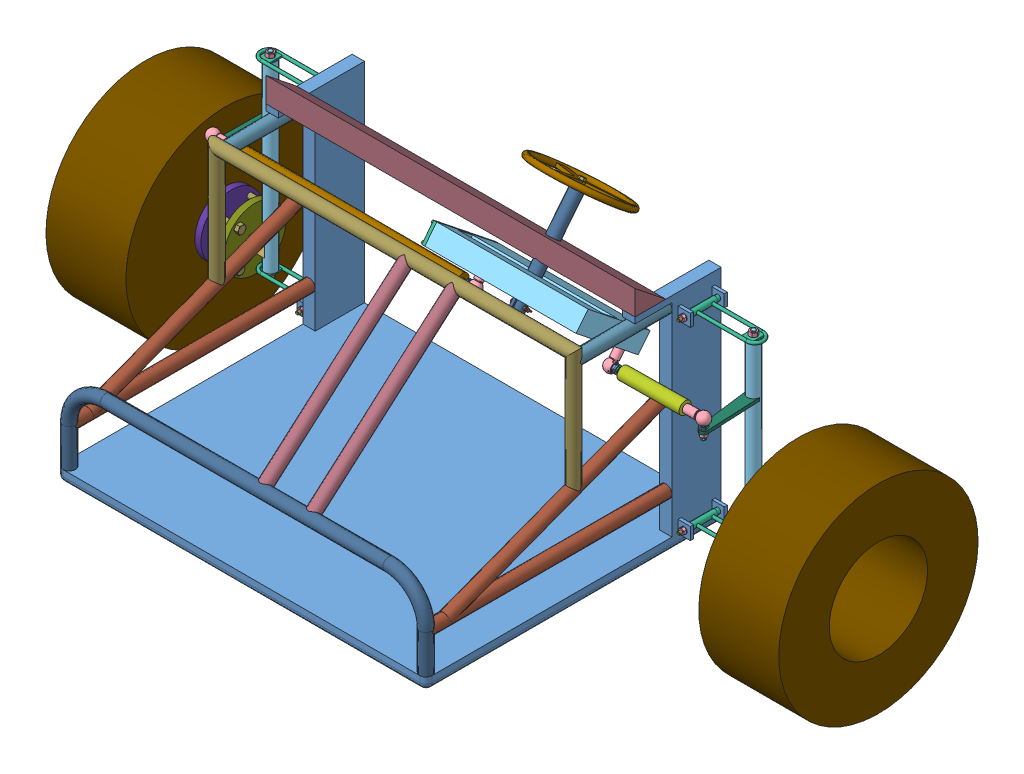
SolidWorks assembly FCA1, configuration Default. Lengths in mm.
Overall size (1513.16 852.83 849.49).
103 component instances, 32 part files, 159 mates.
Components (placement in the parent):
- FCP1-1: FCP1 [Default] at origin size (812.8 457.2 609.6)
- STA1-2: STA1 [Default] at (558.8 334.6162 -409.4012) x (-0.999987 0.003219 0.004024) z (0 0.780869 -0.624695) size (320.68 259.28 240.21)
  - STP10-3: STP10 [Default] at origin size (304.8 155.79 25.4)
    - spur gear_ai-4: spur gear_ai [Inch - Spur gear 6DP 25T 20PA 1FW ---S25N3.0H2.0L1.0S1] x (0 0 1) z (-0.989908 0.141715 0) size (25.4 113.98 114.2)
    - rack spur rectangular_ai-2: rack spur rectangular_ai [Inch - Rack-spur - rectangular 6DP 20PA 1FW 1.5PH 12L---SAll] at (-154.037 -91.44 25.4) size (304.8 42.33 25.4)
  - STP01-11: STP01 [Default] at (138.063 -75.0375 -39.3517) x (0 1 0) z (0 0 -1) size (23.88 20.07 47.75)
  - STP03-3: STP03 [Default] at (150.763 -97.79 31.75) x (0 0 -1) z (1 0 0) size (39.69 165.1 311.15)
  - STP04-3: STP04 [Default] at (150.763 -97.79 -7.9375) x (0 0 1) z (-1 0 0) size (39.69 165.1 6.59)
  - socket head cap screw_ai-1: socket head cap screw_ai [HX-SHCS 0.125-40x0.5x0.5-N] at (160.288 64.135 28.575) x (-1 0 0) z (0 0.866025 0.5) size (15.88 5.21 5.21)
  - socket head cap screw_ai-2: socket head cap screw_ai [HX-SHCS 0.125-40x0.5x0.5-N] at (160.288 64.135 -4.7625) x (-1 0 0) z (0 0.866025 0.5) size (15.88 5.21 5.21)
  - socket head cap screw_ai-4: socket head cap screw_ai [HX-SHCS 0.125-40x0.5x0.5-N] at (160.288 -94.615 28.575) x (-1 0 0) z (0 0.866025 0.5) size (15.88 5.21 5.21)
  - socket head cap screw_ai-7: socket head cap screw_ai [HX-SHCS 0.125-40x0.5x0.5-N] at (160.288 -94.615 -4.7625) x (-1 0 0) z (0 0.866025 0.5) size (15.88 5.21 5.21)
  - STP01-10: STP01 [Default] at (-141.337 -75.0375 -39.3517) x (0 -1 0) z (0 0 -1) size (23.88 20.07 47.75)
  - STP05-2: STP05 [Default] at (-154.037 -58.6317 0) x (1 0 0) z (0 0 -1) size (304.8 32.77 26.99)
  - STP06-1: STP06 [Default] at (-0.0036 -0.0251 180.975) x (0.5 -0.866025 0) z (0 0 1) size (189.81 189.81 12.01)
  - STP07-1: STP07 [Default] at (-0.0036 -0.0251 -33.528) x (-0.141715 -0.989908 0) z (0 0 1) size (28 24.77 211.33)
  - FWP4-1: FWP4 [Default] at (-20.7057 3.2593 -20.828) x (0 0 1) z (0.989908 -0.141715 0) size (12.7 12.7 39.95)
  - hex bolt_ai-1: hex bolt_ai [HBOLT 0.2500-20x0.75x0.75-N] at (-0.0036 -0.0251 188.9252) x (0 0 -1) z (0.5 0.866025 0) size (23.83 12.85 11.13)
- STP08-1: STP08 [Default] at (469.9 381 -431.8) x (0 0 -1) z (1 0 0) size (63.5 50.8 762)
- STP02-1: STP02 [Default] at (889.5958 256.5577 -445.8437) x (-0.961205 0 0.275836) z (0 1 0) size (16.51 16.51 46.05)
- SP3-1: SP3 [Default] at (889.5958 238.8316 -445.8437) x (-0.086724 0 -0.996232) z (0 -1 0) size (120.39 25.32 6.35)
- FWA1-1: FWA1 [Default] at (1025.989 75.5387 -589.4868) x (0 -0.682582 -0.730809) z (-1 0 0) size (411.48 411.48 257.81)
  - FWP5-2: FWP5 [Default] at (27.9791 75.0582 101.7677) size (127 127 48.26)
  - FWP1-1: FWP1 [Default] at (27.9791 75.0582 53.5077) size (127 127 48.26)
  - EB2-1: EB2 [Default] at (27.9791 75.0582 50.3327) x (-1 0 0) z (0 0 1) size (411.48 411.48 165.1)
  - internal tooth-lock washers_ai-1: internal tooth-lock washers_ai [Internal Tooth LW Type A-0.375] at (78.7791 75.0582 49.3167) x (0.992449 -0.122662 0) z (-0.122662 -0.992449 0) size (17.58 1.02 17.58)
  - internal tooth-lock washers_ai-2: internal tooth-lock washers_ai [Internal Tooth LW Type A-0.375] at (-22.8209 75.0582 49.3167) x (0.730809 -0.682582 0) z (-0.682582 -0.730809 0) size (17.58 1.02 17.58)
  - FWP2-2: FWP2 [Default] at (27.9791 75.0582 114.4677) x (-0.730809 0.682582 0) z (0 0 -1) size (9.53 9.53 14.29)
  - FWP3-2: FWP3 [Default] at (19.3103 65.7769 130.3427) x (0 0 1) z (-0.730809 0.682582 0) size (31.75 25.4 25.4)
  - FWP4-1: FWP4 [Default] at (13.8923 59.9761 123.9927) x (-0.730809 0.682582 0) z (0.682582 0.730809 0) size (12.7 12.7 39.95)
  - hex nut_ai-5: hex nut_ai [HNUT 0.4375-20-D-N] at (78.7791 75.0582 49.3167) x (0.291608 -0.956538 0) z (0 0 1) size (17.48 20.18 9.78)
  - internal tooth-lock washers_ai-5: internal tooth-lock washers_ai [Internal Tooth LW Type A-0.375] at (27.9791 24.2582 49.3167) x (-0.875007 -0.484111 0) z (-0.484111 0.875007 0) size (17.58 1.02 17.58)
  - internal tooth-lock washers_ai-6: internal tooth-lock washers_ai [Internal Tooth LW Type A-0.375] at (27.9791 125.8582 49.3167) x (0.730809 -0.682582 0) z (-0.682582 -0.730809 0) size (17.58 1.02 17.58)
  - hex nut_ai-7: hex nut_ai [HNUT 0.4375-20-D-N] at (-22.8209 75.0582 49.3167) x (0.291608 -0.956538 0) z (0 0 1) size (17.48 20.18 9.78)
  - hex nut_ai-8: hex nut_ai [HNUT 0.4375-20-D-N] at (27.9791 24.2582 39.5377) x (-0.97419 0.225729 0) z (0 0 -1) size (17.48 20.18 9.78)
  - hex nut_ai-9: hex nut_ai [HNUT 0.4375-20-D-N] at (27.9791 125.8582 49.3167) x (-0.97419 0.225729 0) z (0 0 1) size (17.48 20.18 9.78)
  - hex bolt_ai-1: hex bolt_ai [HBOLT 0.4375-20x3x1.125-N] at (78.7791 75.0582 122.4941) x (0 0 -1) z (-0.291608 0.956538 0) size (84.23 18.33 15.88)
  - hex bolt_ai-2: hex bolt_ai [HBOLT 0.4375-20x3x1.125-N] at (27.9791 125.8582 122.4941) x (0 0 -1) z (0.682582 0.730809 0) size (84.23 18.33 15.88)
  - hex bolt_ai-3: hex bolt_ai [HBOLT 0.4375-20x3x1.125-N] at (-22.8209 75.0582 122.4941) x (0 0 -1) z (0.97419 -0.225729 0) size (84.23 18.33 15.88)
  - hex bolt_ai-6: hex bolt_ai [HBOLT 0.4375-20x3x1.125-N] at (27.9791 24.2582 122.4941) x (0 0 -1) z (0.97419 -0.225729 0) size (84.23 18.33 15.88)
- SA1-3: SA1 [Default] at (902.3249 84.601 -573.897) x (-0.581832 0 -0.813309) z (0 1 0) size (129.23 145.39 403.48)
  - SS1-1: SS1 [Default] at (0.7633 27.1847 256.5845) x (1 0 0) z (0 0 1) size (25.4 25.4 403.48)
  - SP2-2: SP2 [Default] at (87.3872 94.4048 258.172) x (0.581832 0.813309 0) z (-0.813309 0.581832 0) size (133.34 12.7 63.5)
  - SP2-3: SP2 [Default] at (87.3872 94.4048 -122.701) x (0.581832 0.813309 0) z (-0.813309 0.581832 0) size (133.34 12.7 63.5)
  - hex nut_ai-3: hex nut_ai [HNUT 0.3750-24-D-N] at (0.7633 27.1846 -132.8483) x (0.910536 0.41343 0) z (0 0 -1) size (14.27 16.48 8.56)
  - hex nut_ai-4: hex nut_ai [HNUT 0.3750-24-D-N] at (0.7633 27.1847 268.3193) x (0.910536 0.41343 0) z (0 0 1) size (14.27 16.48 8.56)
- STP09-1: STP09 [Default] at (724.7148 240.1747 -456.9263) x (0.009813 0 0.999952) z (-0.999952 0 0.009813) size (25.4 25.4 152.4)
- STP02-2: STP02 [Default] at (699.7485 256.5577 -443.9807) x (-0.004906 -0.866025 -0.499976) z (-0.999952 0 0.009813) size (16.51 16.51 46.05)
- STP01-3: STP01 [Default] at (889.5958 256.5577 -445.8437) x (0.009813 0 0.999952) z (0.999952 0 -0.009813) size (23.88 20.07 47.75)
- hex bolt_ai-1: hex bolt_ai [HBOLT 0.2500-20x3.5x0.75-N] at (774.7 342.9 -601.6752) x (0 0 1) z (-1 0 0) size (93.68 12.85 11.13)
- external tooth lock washer_ai-1: external tooth lock washer_ai [ASME B18.21.1 - 0.256] at (774.7 342.9 -520.7) x (0 0 -1) z (0.999649 0.026486 0) size (0.58 12.4 12.55)
- hex nut_ai-1: hex nut_ai [HNUT 0.2500-28-D-N] at (774.7 342.9 -514.3754) x (0.5 -0.866025 0) z (0 0 1) size (11.11 12.83 5.74)
- hex bolt_ai-2: hex bolt_ai [HBOLT 0.2500-20x3.5x0.75-N] at (774.7 -38.1 -601.6752) x (0 0 1) z (-0.5 0.866025 0) size (93.68 12.85 11.13)
- external tooth lock washer_ai-2: external tooth lock washer_ai [ASME B18.21.1 - 0.256] at (774.7 -38.1 -520.7) x (0 0 -1) z (0.643979 -0.765044 0) size (0.58 12.4 12.55)
- hex nut_ai-2: hex nut_ai [HNUT 0.2500-28-D-N] at (774.7 -38.1 -514.3754) x (0.5 -0.866025 0) z (0 0 1) size (11.11 12.83 5.74)
- FWA1-2: FWA1 [Default] at (-263.989 -72.2367 -589.4868) x (0 0.682582 -0.730809) z (1 0 0) size (411.48 411.48 257.81)
  - FWP5-2: FWP5 [Default] at (27.9791 75.0582 101.7677) size (127 127 48.26)
  - FWP1-1: FWP1 [Default] at (27.9791 75.0582 53.5077) size (127 127 48.26)
  - EB2-1: EB2 [Default] at (27.9791 75.0582 50.3327) x (-1 0 0) z (0 0 1) size (411.48 411.48 165.1)
  - internal tooth-lock washers_ai-1: internal tooth-lock washers_ai [Internal Tooth LW Type A-0.375] at (78.7791 75.0582 49.3167) x (0.992449 -0.122662 0) z (-0.122662 -0.992449 0) size (17.58 1.02 17.58)
  - internal tooth-lock washers_ai-2: internal tooth-lock washers_ai [Internal Tooth LW Type A-0.375] at (-22.8209 75.0582 49.3167) x (0.730809 -0.682582 0) z (-0.682582 -0.730809 0) size (17.58 1.02 17.58)
  - FWP2-2: FWP2 [Default] at (27.9791 75.0582 114.4677) x (-0.730809 0.682582 0) z (0 0 -1) size (9.53 9.53 14.29)
  - FWP3-2: FWP3 [Default] at (19.3103 65.7769 130.3427) x (0 0 1) z (-0.730809 0.682582 0) size (31.75 25.4 25.4)
  - FWP4-1: FWP4 [Default] at (13.8923 59.9761 123.9927) x (-0.730809 0.682582 0) z (0.682582 0.730809 0) size (12.7 12.7 39.95)
  - hex nut_ai-5: hex nut_ai [HNUT 0.4375-20-D-N] at (78.7791 75.0582 49.3167) x (0.291608 -0.956538 0) z (0 0 1) size (17.48 20.18 9.78)
  - internal tooth-lock washers_ai-5: internal tooth-lock washers_ai [Internal Tooth LW Type A-0.375] at (27.9791 24.2582 49.3167) x (-0.875007 -0.484111 0) z (-0.484111 0.875007 0) size (17.58 1.02 17.58)
  - internal tooth-lock washers_ai-6: internal tooth-lock washers_ai [Internal Tooth LW Type A-0.375] at (27.9791 125.8582 49.3167) x (0.730809 -0.682582 0) z (-0.682582 -0.730809 0) size (17.58 1.02 17.58)
  - hex nut_ai-7: hex nut_ai [HNUT 0.4375-20-D-N] at (-22.8209 75.0582 49.3167) x (0.291608 -0.956538 0) z (0 0 1) size (17.48 20.18 9.78)
  - hex nut_ai-8: hex nut_ai [HNUT 0.4375-20-D-N] at (27.9791 24.2582 39.5377) x (-0.97419 0.225729 0) z (0 0 -1) size (17.48 20.18 9.78)
  - hex nut_ai-9: hex nut_ai [HNUT 0.4375-20-D-N] at (27.9791 125.8582 49.3167) x (-0.97419 0.225729 0) z (0 0 1) size (17.48 20.18 9.78)
  - hex bolt_ai-1: hex bolt_ai [HBOLT 0.4375-20x3x1.125-N] at (78.7791 75.0582 122.4941) x (0 0 -1) z (-0.291608 0.956538 0) size (84.23 18.33 15.88)
  - hex bolt_ai-2: hex bolt_ai [HBOLT 0.4375-20x3x1.125-N] at (27.9791 125.8582 122.4941) x (0 0 -1) z (0.682582 0.730809 0) size (84.23 18.33 15.88)
  - hex bolt_ai-3: hex bolt_ai [HBOLT 0.4375-20x3x1.125-N] at (-22.8209 75.0582 122.4941) x (0 0 -1) z (0.97419 -0.225729 0) size (84.23 18.33 15.88)
  - hex bolt_ai-6: hex bolt_ai [HBOLT 0.4375-20x3x1.125-N] at (27.9791 24.2582 122.4941) x (0 0 -1) z (0.97419 -0.225729 0) size (84.23 18.33 15.88)
- SA1-4: SA1 [Default] at (-140.3249 220.199 -573.897) x (0.581832 0 -0.813309) z (0 -1 0) size (129.23 145.39 403.48)
  - SS1-1: SS1 [Default] at (0.7633 27.1847 256.5845) x (1 0 0) z (0 0 1) size (25.4 25.4 403.48)
  - SP2-2: SP2 [Default] at (87.3872 94.4048 258.172) x (0.581832 0.813309 0) z (-0.813309 0.581832 0) size (133.34 12.7 63.5)
  - SP2-3: SP2 [Default] at (87.3872 94.4048 -122.701) x (0.581832 0.813309 0) z (-0.813309 0.581832 0) size (133.34 12.7 63.5)
  - hex nut_ai-3: hex nut_ai [HNUT 0.3750-24-D-N] at (0.7633 27.1846 -132.8483) x (0.910536 0.41343 0) z (0 0 -1) size (14.27 16.48 8.56)
  - hex nut_ai-4: hex nut_ai [HNUT 0.3750-24-D-N] at (0.7633 27.1847 268.3193) x (0.910536 0.41343 0) z (0 0 1) size (14.27 16.48 8.56)
- hex bolt_ai-4: hex bolt_ai [HBOLT 0.2500-20x3.5x0.75-N] at (-12.7 342.9 -601.6752) x (0 0 1) z (-1 0 0) size (93.68 12.85 11.13)
- external tooth lock washer_ai-9: external tooth lock washer_ai [ASME B18.21.1 - 0.256] at (-12.7 342.9 -520.7) x (0 0 -1) z (0.602564 -0.798071 0) size (0.58 12.4 12.55)
- hex nut_ai-3: hex nut_ai [HNUT 0.2500-28-D-N] at (-12.7 342.9 -514.3754) size (11.11 12.83 5.74)
- SP3-2: SP3 [Default] at (-123.1466 232.2195 -445.5445) x (0.047449 0 -0.998874) z (0 1 0) size (120.39 25.32 6.35)
- hex nut_ai-4: hex nut_ai [HNUT 0.3125-24-D-N] at (889.5958 225.5474 -445.8437) x (0.986789 0 0.162012) z (0 -1 0) size (12.7 14.66 6.93)
- STP010-1: STP010 [Default] at (395.2241 278.1416 -442.6472) x (-0.002815 -0.625306 0.780375) z (0.999986 0.00167 0.004946) size (25.4 25.4 508)
- STP02-3: STP02 [Default] at (420.3522 257.4571 -442.8565) x (0.004395 -0.780378 -0.625293) z (0.999986 0.00167 0.004946) size (16.51 16.51 46.05)
- STP02-4: STP02 [Default] at (-123.1466 256.5497 -445.5445) x (0.666341 0 0.745647) z (0 1 0) size (16.51 16.51 46.05)
- hex nut_ai-5: hex nut_ai [HNUT 0.3125-24-D-N] at (-123.1466 225.2853 -445.5445) x (-0.977382 0 -0.211483) z (0 -1 0) size (12.7 14.66 6.93)
- STP01-5: STP01 [Default] at (-123.1466 256.5497 -445.5445) x (0.005218 -0.342016 -0.93968) z (-0.999986 -0.00167 -0.004946) size (23.88 20.07 47.75)
- hex bolt_ai-5: hex bolt_ai [HBOLT 0.2500-20x3.5x0.75-N] at (-12.7 -37.973 -601.6752) x (0 0 1) z (-1 0 0) size (93.68 12.85 11.13)
- external tooth lock washer_ai-10: external tooth lock washer_ai [ASME B18.21.1 - 0.256] at (-12.7 -37.973 -520.7) x (0 0 -1) z (0.999649 -0.026486 0) size (0.58 12.4 12.55)
- hex nut_ai-6: hex nut_ai [HNUT 0.2500-28-D-N] at (-12.7 -37.973 -520.1158) x (0.5 0.866025 0) z (0 0 -1) size (11.11 12.83 5.74)
- FCP2-1: FCP2 [Default] at (12.7 -50.8 -12.7) size (762 168.4 25.4)
- FCP3-1: FCP3 [Default] at (12.7 25.4 -508) x (0.992649 -0.121026 0) z (0 0 1) size (25.4 25.4 495.3)
- FCP3-2: FCP3 [Default] at (749.3 25.4 -508) size (25.4 25.4 495.3)
- FCP3-4: FCP3 [Default] at (12.7 25.4 -50.8) x (0.846332 0.498186 0.188503) z (0 0.353892 -0.935286) size (25.4 25.4 495.3)
- FCP4-1: FCP4 [Default] at (12.7 127 -317.5) size (762 254 25.4)
- FCP3-6: FCP3 [Default] at (749.3 200.6828 -514.0473) x (1 0 0) z (0 -0.353892 0.935286) size (25.4 25.4 495.3)
- FCP5-1: FCP5 [Default] at (408.6538 104.14 -15.24) x (1 0 0) z (0 -0.658057 0.752969) size (25.4 25.4 401.32)
- FCP5-2: FCP5 [Default] at (508 104.14 -15.24) x (1 0 0) z (0 -0.658057 0.752969) size (25.4 25.4 401.32)
- FCP6-1: FCP6 [Default] at (749.3 355.6 -508) size (25.4 25.4 190.5)
- FCP6-2: FCP6 [Default] at (12.7 355.6 -508) size (25.4 25.4 190.5)
Mates (geometry in assembly coordinates):
- Coincident9: coincident: line of FCP1-1 through (0 381 -609.6) axis (0 0 1); line of STP08-1 through (0 381 -495.3) axis (0 0 1)
- Concentric33: concentric: cylinder of STP02-1 through (889.5958 218.7656 -445.8437) axis (0 1 0) radius 3.4544; circle of SP3-1
- Coincident47: coincident: plane of STP02-1 through (889.5958 238.8316 -445.8437) normal (0 -1 0); circle of SP3-1
- Concentric3939: concentric: circle of FCP1-1; circle of SA1-3/SP2-3
- Coincident5481: coincident: plane of FCP1-1 through (693.6084 0 -590.55) normal (0 0 1); circle of SA1-3/SP2-3
- Angle15: planar angle = 0 rad: plane of SA1-3/SP2-3 through (868.3413 -38.1 -545.592) normal (-1 0 0); plane of FCP1-1 through (736.6 355.6 -25.4) normal (-1 0 0)
- Lock2: lock: unknown of ?; unknown of STP08-1
- Lock3: lock: unknown of FCP1-1; unknown of STP08-1
- Concentric3947: concentric: sphere of STA1-2/STP01-10; sphere of STP02-2
- Angle17: planar angle = 3.141593 rad: plane of STP01-3 through (889.4712 248.6837 -458.5431) normal (0 -1 0); plane of FCP1-1 through (0 -76.2 765.8005) normal (0 -1 0)
- Concentric3948: concentric: sphere of STP02-1; sphere of STP01-3
- Concentric3949: concentric: cylinder of SP3-1 through (879.7713 238.8316 -558.7009) axis (0 -1 0) radius 12.7; cylinder of SA1-3/SS1-1 through (879.7713 -36.5125 -558.7009) axis (0 1 0) radius 12.7
- Concentric3950: concentric: cylinder of FWA1-1/FWP3-2 through (879.7713 -11.1125 -558.7009) axis (0 1 0) radius 12.7; cylinder of SA1-3/SS1-1 through (879.7713 -36.5125 -558.7009) axis (0 1 0) radius 12.7
- Angle18: planar angle = 0 rad: plane of FWA1-1/FWP3-2 through (895.6463 -11.1125 -571.4009) normal (0 0 -1); plane of FCP1-1 through (0 0 -609.6) normal (0 0 -1)
- Distance6: distance = 25.4 mm: plane of FWA1-1/FWP3-2 through (895.6463 -11.1125 -558.7009) normal (0 -1 0); plane of SA1-3/SP2-3 through (774.7 -36.5125 -545.592) normal (0 1 0)
- Concentric3953: concentric: circle of STP09-1; circle of STP02-2
- Coincident5483: coincident: plane of STP09-1 through (737.5389 256.5577 -444.3516) normal (-0.999952 0 0.009813); circle of STP02-2
- Concentric3955: concentric: circle of STP09-1; circle of STP01-3
- Coincident5484: coincident: circle of STP09-1; cone of STP01-3 through (876.8964 256.5577 -445.7191) axis (0.999952 0 -0.009813)
- Concentric39561: concentric: cylinder of FCP1-1 through (774.7 342.9 -520.7) axis (0 0 -1) radius 4.7625; cylinder of hex bolt_ai-1 through (774.7 342.9 -601.6752) axis (0 0 -1) radius 3.175
- Coincident54851: coincident: plane of FCP1-1 through (0 0 -596.9) normal (0 0 -1); plane of hex bolt_ai-1 through (774.7 349.3231 -596.9) normal (0 0 1)
- Concentric39571: concentric: cylinder of FCP1-1 through (774.7 342.9 -520.7) axis (0 0 -1) radius 4.7625; cylinder of external tooth lock washer_ai-1 through (774.7 342.9 -485.775) axis (0 0 1) radius 3.2512
- Coincident54861: coincident: plane of FCP1-1 through (0 0 -520.7) normal (0 0 1); plane of external tooth lock washer_ai-1 through (774.6139 346.1501 -520.7) normal (0 0 -1)
- Concentric39581: concentric: cylinder of external tooth lock washer_ai-1 through (774.7 342.9 -520.1158) axis (0 0 -1) radius 4.7625; cylinder of hex nut_ai-1 through (774.7 342.9 -539.4129) axis (0 0 1) radius 3.175
- Coincident54871: coincident: plane of external tooth lock washer_ai-1 through (774.5338 349.1716 -520.1158) normal (0 0 1); plane of hex nut_ai-1 through (780.2563 346.1079 -520.1158) normal (0 0 -1)
- Concentric39601: concentric: cylinder of FCP1-1 through (774.7 -38.1 -520.7) axis (0 0 -1) radius 4.7625; cylinder of hex bolt_ai-2 through (774.7 -38.1 -601.6752) axis (0 0 -1) radius 3.175
- Coincident54891: coincident: plane of FCP1-1 through (0 304.8 -596.9) normal (0 0 -1); plane of hex bolt_ai-2 through (780.2626 -34.8884 -596.9) normal (0 0 1)
- Concentric39611: concentric: cylinder of FCP1-1 through (774.7 -38.1 -520.7) axis (0 0 -1) radius 4.7625; cylinder of external tooth lock washer_ai-2 through (774.7 -38.1 -485.775) axis (0 0 1) radius 3.2512
- Coincident54901: coincident: plane of FCP1-1 through (0 304.8 -520.7) normal (0 0 1); plane of external tooth lock washer_ai-2 through (777.1873 -36.0063 -520.7) normal (0 0 -1)
- Concentric39621: concentric: cylinder of external tooth lock washer_ai-2 through (774.7 -38.1 -520.1158) axis (0 0 -1) radius 4.7625; cylinder of hex nut_ai-2 through (774.7 -38.1 -539.4129) axis (0 0 1) radius 3.175
- Coincident54911: coincident: plane of external tooth lock washer_ai-2 through (779.4997 -34.0598 -520.1158) normal (0 0 1); plane of hex nut_ai-2 through (780.2563 -34.8921 -520.1158) normal (0 0 -1)
- Concentric3964: concentric: circle of FCP1-1; circle of SA1-4/SP2-3
- Coincident5492: coincident: plane of FCP1-1 through (411.331 355.6 -527.05) normal (0 0 -1); circle of SA1-4/SP2-3
- Concentric39671: concentric: cylinder of FCP1-1 through (-12.7 342.9 -520.7) axis (0 0 -1) radius 4.7625; cylinder of hex bolt_ai-4 through (-12.7 342.9 -601.6752) axis (0 0 -1) radius 3.175
- Coincident54951: coincident: plane of FCP1-1 through (762 0 -596.9) normal (0 0 -1); plane of hex bolt_ai-4 through (-12.7 349.3231 -596.9) normal (0 0 1)
- Concentric39721: concentric: cylinder of FCP1-1 through (-12.7 342.9 -520.7) axis (0 0 -1) radius 4.7625; cylinder of external tooth lock washer_ai-9 through (-12.7 342.9 -485.775) axis (0 0 1) radius 3.2512
- Coincident54961: coincident: plane of FCP1-1 through (762 0 -520.7) normal (0 0 1); plane of external tooth lock washer_ai-9 through (-10.1053 344.8591 -520.7) normal (0 0 -1)
- Concentric39731: concentric: cylinder of external tooth lock washer_ai-9 through (-12.7 342.9 -520.1158) axis (0 0 -1) radius 4.7625; cylinder of hex nut_ai-3 through (-12.7 342.9 -539.4129) axis (0 0 1) radius 3.175
- Coincident54971: coincident: plane of external tooth lock washer_ai-9 through (-7.6931 346.6804 -520.1158) normal (0 0 1); plane of hex nut_ai-3 through (-12.7 349.3158 -520.1158) normal (0 0 -1)
- Concentric3974: concentric: cylinder of FWA1-2/FWP3-2 through (-117.7713 14.4145 -558.7009) axis (0 -1 0) radius 12.7; cylinder of SA1-4/SS1-1 through (-117.7713 341.3125 -558.7009) axis (0 -1 0) radius 12.7
- Parallel4: parallel: plane of FCP1-1 through (0 0 -609.6) normal (-1 0 0); plane of FWA1-2/FWP5-2 through (-149.5213 1.7145 -558.7009) normal (1 0 0)
- Distance7: distance = 25.4 mm: plane of FWA1-2/FWP3-2 through (-133.6463 -10.9855 -558.7009) normal (0 -1 0); plane of SA1-4/SP2-2 through (-12.7 -36.3855 -545.592) normal (0 1 0)
- Concentric3975: concentric: cylinder of SA1-4/SS1-1 through (-117.7713 341.3125 -558.7009) axis (0 -1 0) radius 12.7; cylinder of SP3-2 through (-117.7713 232.2195 -558.7009) axis (0 1 0) radius 12.7
- Concentric39771: concentric: cylinder of SP3-1 through (889.9024 232.2194 -445.8708) axis (0 1 0) radius 3.937; cylinder of ? through (889.9024 231.3558 -445.8708) axis (0 1 0) radius 7.747
- Coincident55001: coincident: plane of SP3-1 through (889.9024 232.2194 -445.8708) normal (0 -1 0); plane of ? through (889.9024 232.2194 -445.8708) normal (0 1 0)
- Concentric39781: concentric: cylinder of ? through (889.9024 232.2194 -445.8708) axis (0 -1 0) radius 5.4813; cylinder of hex nut_ai-4 through (889.9024 249.4591 -445.8708) axis (0 -1 0) radius 3.9688
- Coincident55021: coincident: plane of ? through (889.9024 231.3558 -445.8708) normal (0 -1 0); plane of hex nut_ai-4 through (889.9024 231.3558 -438.5384) normal (0 1 0)
- Concentric3979: concentric: cylinder of STP02-3 through (382.5605 257.394 -443.0434) axis (0.999986 0.00167 0.004946) radius 3.4544; circle of STP010-1
- Coincident5503: coincident: plane of STP010-1 through (382.5605 257.394 -443.0434) normal (0.999986 0.00167 0.004946); plane of STP02-3 through (382.5605 257.394 -443.0434) normal (-0.999986 -0.00167 -0.004946)
- Concentric3980: concentric: sphere of STA1-2/STP01-11; sphere of STP02-3
- Concentric3981: concentric: cylinder of SP3-2 through (-123.1466 238.5695 -445.5445) axis (0 -1 0) radius 3.937; cylinder of STP02-4 through (-123.1466 218.7575 -445.5445) axis (0 1 0) radius 3.4544
- Distance8: distance = 2.794 mm: plane of STP02-4 through (-123.1466 241.3635 -445.5445) normal (0 -1 0); plane of SP3-2 through (-123.1466 238.5695 -445.5445) normal (0 1 0)
- Concentric39821: concentric: cylinder of SP3-2 through (-123.1459 238.5695 -445.5444) axis (0 -1 0) radius 8.128; cylinder of ? through (-123.1459 231.3559 -445.5444) axis (0 1 0) radius 7.747
- Coincident55051: coincident: plane of SP3-2 through (-123.1459 232.2195 -445.5444) normal (0 -1 0); plane of ? through (-123.1459 232.2195 -445.5444) normal (0 1 0)
- Concentric39831: concentric: cylinder of ? through (-123.1459 231.3559 -445.5444) axis (0 1 0) radius 7.747; cylinder of hex nut_ai-5 through (-123.1459 249.4592 -445.5444) axis (0 -1 0) radius 3.9688
- Coincident55061: coincident: plane of ? through (-123.1459 231.3559 -445.5444) normal (0 -1 0); plane of hex nut_ai-5 through (-121.5952 231.3559 -452.7109) normal (0 1 0)
- Concentric3988: concentric: circle of STP010-1; circle of STP01-5
- Concentric3989: concentric: sphere of STP02-4; sphere of STP01-5
- Distance9: distance = 105.918 mm: plane of SP3-2 through (-123.1466 238.5695 -445.5445) normal (0 1 0); plane of SA1-4/SP2-3 through (-12.7 344.4875 -545.592) normal (0 1 0)
- Parallel5: parallel: plane of FCP1-1 through (762 330.2 -520.7) normal (0 -1 0); plane of STP09-1 through (876.8595 256.5577 -443.2471) normal (0 -1 0)
- Parallel15: parallel: plane of STP010-1 through (-112.3428 255.0223 -443.5623) normal (-0.004395 0.780378 0.625293); plane of STP02-3 through (405.1502 265.2832 -442.3363) normal (-0.004395 0.780378 0.625293)
- Concentric398321: concentric: cylinder of FCP1-1 through (-12.7 -38.1 -520.7) axis (0 0 -1) radius 4.7625; cylinder of ? through (-12.7 -38.1 -601.6752) axis (0 0 -1) radius 3.175
- Coincident550701: coincident: plane of FCP1-1 through (762 304.8 -596.9) normal (0 0 -1); plane of ? through (-12.7 -31.6769 -596.9) normal (0 0 1)
- Concentric398341: concentric: cylinder of FCP1-1 through (-12.7 -38.1 -520.7) axis (0 0 -1) radius 4.7625; cylinder of ? through (-12.7 -38.1 -485.775) axis (0 0 1) radius 3.2512
- Coincident550711: coincident: plane of FCP1-1 through (762 304.8 -520.7) normal (0 0 1); plane of ? through (-12.7 -34.8488 -520.7) normal (0 0 -1)
- Concentric398351: concentric: cylinder of ? through (-12.7 -38.1 -485.775) axis (0 0 1) radius 3.2512; cylinder of ? through (-12.7 -38.1 -539.4129) axis (0 0 1) radius 3.175
- Coincident550721: coincident: plane of ? through (-12.7 -31.8262 -520.1158) normal (0 0 1); plane of ? through (-12.7 -31.6842 -520.1158) normal (0 0 -1)
- Parallel16: parallel: plane of FCP1-1 through (762 0 -609.6) normal (1 0 0); plane of hex nut_ai-2
- Parallel18: parallel: plane of FCP1-1 through (762 -25.4 -520.7) normal (0 1 0); plane of external tooth lock washer_ai-2
- Parallel19: parallel: plane of FCP1-1 through (762 0 -609.6) normal (1 0 0); plane of hex bolt_ai-2
- Parallel20: parallel: plane of FCP1-1 through (762 0 -609.6) normal (1 0 0); plane of hex bolt_ai-1
- Parallel21: parallel: plane of FCP1-1 through (762 0 -609.6) normal (1 0 0); plane of hex nut_ai-1
- Parallel22: parallel: plane of FCP1-1 through (762 355.6 -520.7) normal (0 1 0); plane of external tooth lock washer_ai-1
- Parallel23: parallel: plane of FCP1-1 through (762 0 -609.6) normal (1 0 0); plane of hex nut_ai-2
- Parallel24: parallel: plane of FCP1-1 through (762 -25.4 -520.7) normal (0 1 0); plane of external tooth lock washer_ai-2
- Parallel25: parallel: plane of FCP1-1 through (762 0 -609.6) normal (1 0 0); plane of hex bolt_ai-2
- Parallel26: parallel: plane of FCP1-1 through (762 0 -609.6) normal (1 0 0); plane of hex bolt_ai-1
- Parallel27: parallel: plane of FCP1-1 through (762 0 -609.6) normal (1 0 0); plane of hex nut_ai-1
- Parallel28: parallel: plane of FCP1-1 through (762 355.6 -520.7) normal (0 1 0); plane of external tooth lock washer_ai-1
- Parallel29: parallel: plane of FCP1-1 through (0 0 -609.6) normal (-1 0 0); plane of hex nut_ai-3
- Parallel30: parallel: plane of FCP1-1 through (0 0 -609.6) normal (-1 0 0); plane of hex bolt_ai-4 through (-18.2626 346.1116 -596.9) normal (-1 0 0)
- Parallel33: parallel: plane of FCP1-1 through (-25.4 355.6 -520.7) normal (-1 0 0); plane of external tooth lock washer_ai-9 through (-14.3554 349.2761 -520.1158) normal (-1 0 0)
- Concentric398371: concentric: cylinder of FCP1-1 through (-12.7 -38.1 -520.7) axis (0 0 -1) radius 4.7625; cylinder of ? through (-12.7 -38.1 -601.6752) axis (0 0 -1) radius 3.175
- Coincident550911: coincident: plane of FCP1-1 through (762 304.8 -596.9) normal (0 0 -1); plane of ? through (-12.7 -31.6769 -596.9) normal (0 0 1)
- Parallel34: parallel: plane of ? through (-18.2626 -34.8884 -596.9) normal (-1 0 0); plane of FCP1-1 through (0 0 -609.6) normal (-1 0 0)
- Concentric398381: concentric: cylinder of FCP1-1 through (-12.7 -38.1 -520.7) axis (0 0 -1) radius 4.7625; cylinder of hex bolt_ai-5 through (-12.7 -38.1 -601.6752) axis (0 0 -1) radius 3.175
- Coincident550931: coincident: plane of FCP1-1 through (762 304.8 -596.9) normal (0 0 -1); plane of hex bolt_ai-5 through (-12.7 -31.6769 -596.9) normal (0 0 1)
- Parallel35: parallel: plane of FCP1-1 through (0 0 -609.6) normal (-1 0 0); plane of hex bolt_ai-5 through (-18.2626 -34.8884 -596.9) normal (-1 0 0)
- Concentric398391: concentric: cylinder of FCP1-1 through (-12.7 -38.1 -520.7) axis (0 0 -1) radius 4.7625; cylinder of external tooth lock washer_ai-10 through (-12.7 -38.1 -485.775) axis (0 0 1) radius 3.2512
- Coincident550951: coincident: plane of FCP1-1 through (762 304.8 -520.7) normal (0 0 1); plane of external tooth lock washer_ai-10 through (-12.6139 -34.8499 -520.7) normal (0 0 -1)
- Concentric398401: concentric: cylinder of external tooth lock washer_ai-10 through (-12.7 -38.1 -520.1158) axis (0 0 -1) radius 4.7625; cylinder of hex nut_ai-6 through (-12.7 -38.1 -539.4129) axis (0 0 1) radius 3.175
- Coincident550961: coincident: plane of external tooth lock washer_ai-10 through (-12.5338 -31.8284 -520.1158) normal (0 0 1); plane of hex nut_ai-6
- Parallel36: parallel: plane of FCP1-1 through (-25.4 -50.8 -520.7) normal (-1 0 0); plane of external tooth lock washer_ai-10 through (-14.3554 -31.7239 -520.1158) normal (-1 0 0)
- Parallel37: parallel: plane of FCP1-1 through (-25.4 -50.8 -520.7) normal (-1 0 0); plane of hex nut_ai-6
- Parallel38: parallel: plane of STP010-1; plane of STP02-3
- Parallel39: parallel: plane of FCP1-1 through (0 0 -609.6) normal (-1 0 0); plane of hex bolt_ai-5 through (-18.2626 -34.8884 -596.9) normal (-1 0 0)
- Parallel40: parallel: plane of STP010-1; plane of STP02-3
- Parallel43: parallel: plane of STP010-1; plane of STP02-3
- Angle22: planar angle = 0.349066 rad: plane of STP02-3 through (405.1502 265.2832 -442.3363) normal (-0.004395 0.780378 0.625293); plane of STA1-2/STP04-3 through (402.036 370.9715 -351.2509) normal (0.005153 0.624687 0.780858)
- Parallel49: parallel: plane of STP02-4; plane of hex nut_ai-5
- Parallel52: parallel: plane of FCP1-1 through (0 0 -609.6) normal (-1 0 0); plane of STP02-4
- Parallel53: parallel: plane of FCP1-1 through (0 -50.8 -508) normal (0 0 1); plane of ?
- Parallel65: parallel: plane of STP02-1; plane of hex nut_ai-4
- Parallel68: parallel: plane of STP02-1 through (896.4017 241.1094 -441.4258) normal (1 0 0); plane of ? through (889.1996 232.2194 -440.4347) normal (1 0 0)
- Angle26: planar angle = 0 rad: plane of hex nut_ai-4 through (895.2679 232.4816 -441.1972) normal (0.353088 0 0.93559); plane of FCP1-1 through (762 0 -609.6) normal (1 0 0)
- Coincident55128: coincident: plane of STP010-1 through (-87.3445 277.1906 -447.6769) normal (-0.999985 -0.001187 -0.005332); circle of STP01-5
- Angle35: planar angle = 0.201511 rad: plane of STP01-5 through (-123.2138 253.4942 -430.9175) normal (-0.000123 -0.939693 0.34202); plane of STP02-4 through (-123.1466 241.3635 -445.5445) normal (0 -1 0)
- Coincident55142: coincident: plane of STP010-1 through (-87.3693 277.3358 -445.0339) normal (-0.999986 -0.00167 -0.004946); plane of STP01-5 through (-87.3331 256.6095 -445.3673) normal (0.999986 0.00167 0.004946)
- Angle36: planar angle = 2.792527 rad: plane of STP01-5 through (-123.2138 253.4942 -430.9175) normal (-0.000123 -0.939693 0.34202); plane of SP3-2 through (-123.1466 238.5695 -445.5445) normal (0 1 0)
- Angle37: planar angle = 0.89529 rad: plane of STP010-1 through (-112.3428 255.0223 -443.5623) normal (-0.004395 0.780378 0.625293); plane of FCP1-1 through (0 -50.8 -508) normal (0 0 1)
- Angle38: planar angle = 2.412302 rad: plane of STP02-4 through (-115.5014 241.3635 -443.6601) normal (0.666341 0 0.745647); plane of FCP1-1 through (0 -50.8 -508) normal (0 0 1)
- Angle39: planar angle = 0.736691 rad: plane of hex nut_ai-5 through (-124.6973 232.2195 -438.378) normal (-0.67184 0 0.740696); plane of FCP1-1 through (0 -50.8 -508) normal (0 0 1)
- Parallel90: parallel: plane of STP02-4 through (-115.5007 241.3635 -443.6601) normal (0.666341 0 0.745647); plane of ? through (-126.731 232.2195 -441.3982) normal (-0.666341 0 -0.745647)
- Concentric39847: concentric: circle of SP3-2; circle of hex nut_ai-5
- Coincident55149: coincident: plane of SP3-2 through (-123.1466 232.2195 -445.5445) normal (0 -1 0); plane of hex nut_ai-5 through (-121.5959 232.2195 -452.711) normal (0 1 0)
- Angle41: planar angle = 0.442189 rad: plane of STP02-1 through (897.0691 241.3716 -443.3639) normal (0.961205 0 -0.275836); plane of hex nut_ai-4 through (895.2679 232.4816 -441.1972) normal (0.986789 0 0.162012)
- Concentric39848: concentric: circle of SP3-1; circle of hex nut_ai-4
- Coincident55153: coincident: plane of SP3-1 through (889.5958 232.4816 -445.8437) normal (0 -1 0); plane of hex nut_ai-4 through (888.4078 232.4816 -438.6082) normal (0 1 0)
- Angle42: planar angle = 0.166784 rad: plane of hex nut_ai-4 through (895.2679 232.4816 -441.1972) normal (0.986789 0 0.162012); plane of STA1-2/STP03-3 through (718.681 297.8044 -506.2407) normal (0.999987 -0.003219 -0.004024)
- Parallel94: parallel: plane of FCP1-1 through (787.4 -50.8 -520.7) normal (1 0 0); plane of hex nut_ai-2 through (780.2563 -41.3079 -520.1158) normal (1 0 0)
- Parallel95: parallel: plane of FCP1-1 through (787.4 -50.8 -520.7) normal (1 0 0); plane of external tooth lock washer_ai-2 through (776.3554 -31.7239 -520.1158) normal (1 0 0)
- Parallel96: parallel: plane of FCP1-1 through (762 0 -609.6) normal (1 0 0); plane of hex bolt_ai-2 through (780.2626 -41.3116 -596.9) normal (1 0 0)
- Parallel97: parallel: plane of FCP1-1 through (787.4 355.6 -520.7) normal (1 0 0); plane of hex nut_ai-1 through (780.2563 339.6921 -520.1158) normal (1 0 0)
- Parallel98: parallel: plane of FCP1-1 through (787.4 355.6 -520.7) normal (1 0 0); plane of external tooth lock washer_ai-1 through (776.3554 349.2761 -520.1158) normal (1 0 0)
- Parallel99: parallel: plane of FCP1-1 through (787.4 355.6 -520.7) normal (1 0 0); plane of hex bolt_ai-1 through (780.2626 346.1116 -596.9) normal (1 0 0)
- Parallel100: parallel: plane of FCP1-1 through (-25.4 355.6 -520.7) normal (-1 0 0); plane of hex nut_ai-3 through (-18.2563 346.1079 -520.1158) normal (-1 0 0)
- Parallel101: parallel: plane of FCP1-1 through (-25.4 355.6 -520.7) normal (-1 0 0); plane of external tooth lock washer_ai-9 through (-14.3554 349.2761 -520.1158) normal (-1 0 0)
- Parallel102: parallel: plane of FCP1-1 through (-25.4 355.6 -520.7) normal (-1 0 0); plane of hex bolt_ai-4 through (-18.2626 346.1116 -596.9) normal (-1 0 0)
- Concentric39849: concentric: cylinder of SA1-4/SP2-2 through (-12.7 -37.973 -527.05) axis (0 0 -1) radius 3.9688; cylinder of hex bolt_ai-5 through (-12.7 -37.973 -601.6752) axis (0 0 -1) radius 3.175
- Coincident55164: coincident: plane of FCP1-1 through (762 304.8 -596.9) normal (0 0 -1); line of hex bolt_ai-5 through (-18.2626 -34.7614 -596.9) axis (0 -1 0)
- Parallel103: parallel: plane of FCP1-1 through (-25.4 -50.8 -520.7) normal (-1 0 0); plane of hex bolt_ai-5 through (-18.2626 -34.7614 -596.9) normal (-1 0 0)
- Concentric39851: concentric: circle of hex bolt_ai-5; circle of external tooth lock washer_ai-10
- Coincident55166: coincident: plane of FCP1-1 through (762 304.8 -520.7) normal (0 0 1); line of external tooth lock washer_ai-10 through (-9.0009 -32.9058 -520.7) axis (-0.781831 -0.62349 0)
- Concentric39852: concentric: circle of hex bolt_ai-5; circle of hex nut_ai-6
- Coincident55167: coincident: plane of external tooth lock washer_ai-10 through (-12.5338 -31.7014 -520.1158) normal (0 0 1); circle of hex nut_ai-6
- Parallel104: parallel: plane of FCP1-1 through (-25.4 -50.8 -520.7) normal (-1 0 0); plane of external tooth lock washer_ai-10 through (-14.3554 -31.5969 -520.1158) normal (-1 0 0)
- Parallel105: parallel: plane of FCP1-1 through (-25.4 -50.8 -520.7) normal (-1 0 0); plane of hex nut_ai-6 through (-18.2563 -41.1809 -514.3754) normal (-1 0 0)
- Angle43: planar angle = 0.523599 rad: plane of STP02-2 through (715.0036 259.9639 -437.0309) normal (0.004906 0.866025 0.499976); plane of SP3-1 through (889.5958 238.8316 -445.8437) normal (0 1 0)
- Coincident550962: coincident: line of FCP1-1 through (12.7 25.2017 -12.7) axis (0 -1 0); line of FCP2-1 through (12.7 -50.8 -12.7) axis (0 1 0)
- Coincident550964: coincident: circle of FCP1-1; circle of FCP2-1
- Concentric398402: concentric: circle of FCP1-1; cylinder of FCP3-1 through (12.7 25.4 -12.7) axis (0 0 -1) radius 8.7312
- Coincident550965: coincident: plane of FCP1-1 through (0 -50.8 -508) normal (0 0 1); circle of FCP3-1
- Concentric398403: concentric: line of FCP1-1 through (749.3 25.4 -12.7) axis (0 0 -1); circle of FCP3-2
- Coincident550966: coincident: plane of FCP1-1 through (0 -50.8 -508) normal (0 0 1); circle of FCP3-2
- Concentric398404: concentric: line of FCP1-1 through (12.7 368.3 -317.5) axis (0 -1 0); cylinder of FCP4-1 through (12.7 127 -317.5) axis (0 1 0) radius 12.7
- Coincident550970: coincident: circle of FCP1-1; circle of FCP4-1
- Concentric398406: concentric: line of FCP1-1 through (12.7 203.2 -520.7) axis (0 -0.353892 0.935286); circle of FCP3-4
- Coincident550975: coincident: point of FCP1-1; point of FCP3-4
- Concentric398409: concentric: circle of FCP1-1; circle of FCP3-1
- Concentric398410: concentric: line of FCP1-1 through (749.3 25.4 -50.8) axis (0 0.353892 -0.935286); circle of FCP3-6
- Coincident550980: coincident: circle of FCP1-1; plane of FCP3-6 through (749.3 25.4 -50.8) normal (0 -0.353892 0.935286)
- Concentric398411: concentric: circle of FCP1-1; circle of FCP5-1
- Coincident550982: coincident: circle of FCP1-1; circle of FCP5-1
- Concentric398412: concentric: circle of FCP1-1; circle of FCP5-2
- Coincident550984: coincident: circle of FCP1-1; circle of FCP5-2
- Concentric398413: concentric: circle of FCP1-1; circle of FCP6-1
- Coincident550987: coincident: circle of FCP1-1; circle of FCP6-1
- Concentric398414: concentric: circle of FCP1-1; circle of FCP6-2
- Coincident550990: coincident: plane of FCP1-1 through (0 -50.8 -508) normal (0 0 1); circle of FCP6-2
